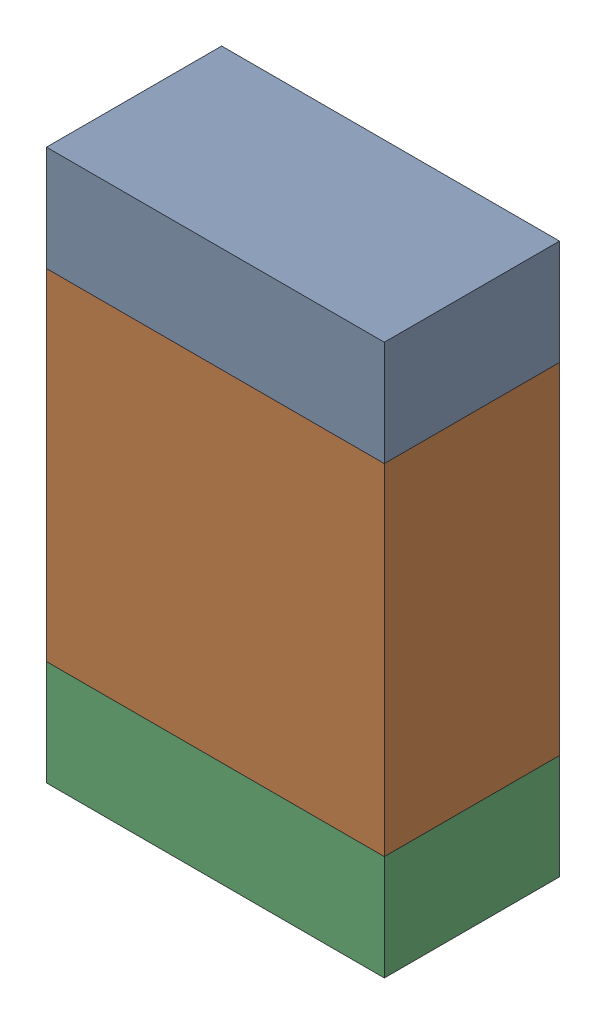
SolidWorks assembly R3-1, configuration Default. Lengths in mm.
Overall size (1.35 2.2 0.7).
6 component instances, 2 part files, 0 mates.
Components (placement in the parent):
- 959207304-1-1: 959207304-1 [Default] at (114.1729 78.1061 0) size (1.35 0.42 0.7)
  - Extruded-39-1: Extruded-39 [Default] at origin size (1.35 0.42 0.7)
- 959207440-1-1: 959207440-1 [Default] at (114.1729 77.2161 0) size (1.35 1.36 0.7)
  - Extruded-40-1: Extruded-40 [Default] at origin size (1.35 1.36 0.7)
- 959207304-1-2: 959207304-1 [Default] at (114.1729 76.3261 0) size (1.35 0.42 0.7)
  - Extruded-39-1: Extruded-39 [Default] at origin size (1.35 0.42 0.7)
